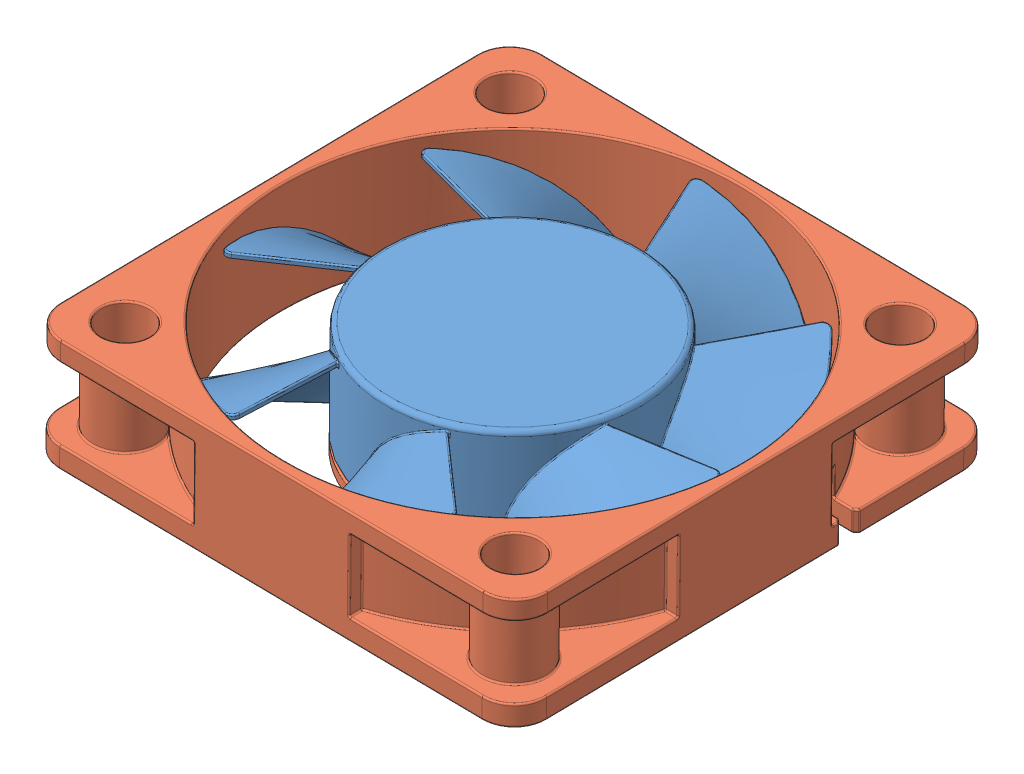
SolidWorks assembly final_assembly, configuration Default. Lengths in mm.
Overall size (31.23 8.1 31.18).
2 component instances, 2 part files, 2 mates.
Components (placement in the parent):
- RotorBlades-1: RotorBlades [Default] at (8.6141 60.8719 15.8846) x (0.997386 -0.019795 -0.069495) z (0.069287 -0.011021 0.997536) size (29.14 7.16 29.16)
- MotorHouse-3: MotorHouse [Default] at (8.5956 59.9722 15.8759) x (0.99977 -0.020451 -0.006458) z (0.006259 -0.009751 0.999933) size (30 7.03 30)
Mates (geometry in assembly coordinates):
- Concentric2: concentric: cylinder of RotorBlades-1 through (8.7252 66.2905 15.9367) axis (-0.020512 -0.999743 -0.009621) radius 0.8; cylinder of MotorHouse-3 through (8.5463 57.5686 15.8528) axis (0.020512 0.999743 0.009621) radius 0.85
- LimitDistance1: limit distance = 0 mm: plane of RotorBlades-1 through (8.7392 66.9704 15.9433) normal (0.020512 0.999743 0.009621); plane of MotorHouse-3 through (21.8176 66.5777 28.8585) normal (0.020512 0.999743 0.009621)
